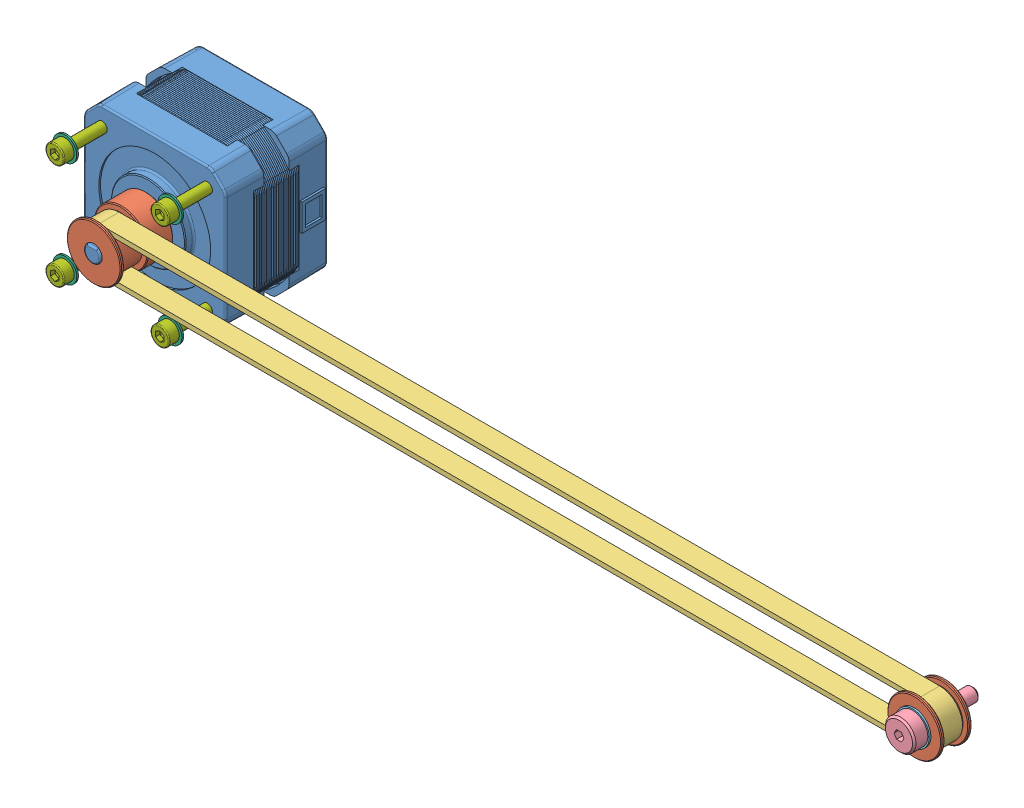
SolidWorks assembly Motion system, configuration Default. Lengths in mm.
Overall size (274.3 42.3 52.5).
15 component instances, 7 part files, 28 mates.
Components (placement in the parent):
- Stepper motor-1: Stepper motor [Default] at (52.9684 86.854 64.8512) x (1 0 0) z (0 -1 0) size (42.8 48.5 42.3)
- 2GT driving pulley-1: 2GT driving pulley [20T long] at (52.9684 86.854 78.3512) x (1 0 0) z (0 -1 0) size (16 15.5 16)
- 2GT driving pulley-2: 2GT driving pulley [20T short] at (294.9684 86.854 84.8512) x (0.57818 -0.815909 0) z (-0.815909 -0.57818 0) size (16 9 16)
- Belt^Motion system-1: Belt^Motion system [Default] at (47.0093 90.3514 89.3512) size (255.49 13.49 6) (virtual)
- Shoulder screw-1: Shoulder screw [Default] at (294.9684 86.854 76.3512) x (1 0 0) z (0 -1 0) size (9 22 9)
- shim-support ring2_din-1: shim-support ring2_din [DIN 988-5x10x0.5] at (294.9684 86.854 84.8512) x (0 0 -1) z (1 0 0) size (0.5 9.81 9.81)
- shim-support ring2_din-2: shim-support ring2_din [DIN 988-5x10x0.5] at (294.9684 86.854 93.8512) x (0 0 1) z (-1 0 0) size (0.5 9.81 9.81)
- plain washer grade a_din-1: plain washer grade a_din [Washer DIN 125 - A 3.2] at (68.4684 71.354 86.3512) x (0 0 -1) z (1 0 0) size (0.5 7 7)
- plain washer grade a_din-2: plain washer grade a_din [Washer DIN 125 - A 3.2] at (37.4684 71.354 86.3512) x (0 0 -1) z (1 0 0) size (0.5 7 7)
- plain washer grade a_din-3: plain washer grade a_din [Washer DIN 125 - A 3.2] at (68.4684 102.354 86.3512) x (0 0 -1) z (1 0 0) size (0.5 7 7)
- plain washer grade a_din-4: plain washer grade a_din [Washer DIN 125 - A 3.2] at (37.4684 102.354 86.3512) x (0 0 -1) z (1 0 0) size (0.5 7 7)
- socket head cap screw_din-1: socket head cap screw_din [DIN 912 M3 x 16 --- 16N] at (68.4684 71.354 89.8512) x (0 0 -1) z (1 0 0) size (19 5.5 5.5)
- socket head cap screw_din-2: socket head cap screw_din [DIN 912 M3 x 16 --- 16N] at (37.4684 71.354 89.8512) x (0 0 -1) z (1 0 0) size (19 5.5 5.5)
- socket head cap screw_din-3: socket head cap screw_din [DIN 912 M3 x 16 --- 16N] at (37.4684 102.354 89.8512) x (0 0 -1) z (1 0 0) size (19 5.5 5.5)
- socket head cap screw_din-4: socket head cap screw_din [DIN 912 M3 x 16 --- 16N] at (68.4684 102.354 89.8512) x (0 0 -1) z (1 0 0) size (19 5.5 5.5)
Mates (geometry in assembly coordinates):
- Concentric21: concentric anti-aligned: cylinder of Shoulder screw-1 through (294.9684 86.854 76.8512) axis (0 0 -1) radius 2.5; cylinder of shim-support ring2_din-1 through (294.9684 86.854 84.8512) axis (0 0 1) radius 2.515
- Coincident20: coincident anti-aligned: plane of Shoulder screw-1 through (299.4684 86.854 94.8512) normal (0 0 -1); plane of shim-support ring2_din-2 through (294.9684 86.854 94.8512) normal (0 0 1)
- Concentric22: concentric anti-aligned: cylinder of shim-support ring2_din-1 through (294.9684 86.854 84.8512) axis (0 0 1) radius 4.905; cylinder of shim-support ring2_din-2 through (294.9684 86.854 94.8512) axis (0 0 -1) radius 4.905
- Coincident12: coincident anti-aligned: plane of plain washer grade a_din-1 through (68.4684 74.854 86.8512) normal (0 0 1); plane of socket head cap screw_din-1 through (68.4684 74.104 86.8512) normal (0 0 -1)
- Coincident13: coincident anti-aligned: plane of plain washer grade a_din-2 through (37.4684 74.854 86.8512) normal (0 0 1); plane of socket head cap screw_din-2 through (37.4684 74.104 86.8512) normal (0 0 -1)
- Coincident15: coincident anti-aligned: plane of plain washer grade a_din-3 through (68.4684 105.854 86.8512) normal (0 0 1); plane of socket head cap screw_din-4 through (68.4684 105.104 86.8512) normal (0 0 -1)
- Coincident14: coincident anti-aligned: plane of plain washer grade a_din-4 through (37.4684 105.854 86.8512) normal (0 0 1); plane of socket head cap screw_din-3 through (37.4684 105.104 86.8512) normal (0 0 -1)
- Distance2: distance = 10.5 mm anti-aligned: plane of Stepper motor-1 through (52.9684 86.854 75.8512) normal (0 0 1); plane of plain washer grade a_din-4 through (37.4684 103.954 86.3512) normal (0 0 -1)
- Coincident22: coincident aligned: plane of plain washer grade a_din-3 through (68.4684 103.954 86.3512) normal (0 0 -1); plane of plain washer grade a_din-4 through (37.4684 103.954 86.3512) normal (0 0 -1)
- Concentric24: concentric aligned: cylinder of plain washer grade a_din-3 through (68.4684 102.354 121.2762) axis (0 0 1) radius 1.6; cylinder of socket head cap screw_din-4 through (68.4684 102.354 121.6012) axis (0 0 1) radius 1.5
- Concentric25: concentric aligned: cylinder of Stepper motor-1 through (68.4684 102.354 70.8512) axis (0 0 1) radius 1.25; cylinder of socket head cap screw_din-4 through (68.4684 102.354 121.6012) axis (0 0 1) radius 1.5
- Concentric26: concentric aligned: cylinder of Stepper motor-1 through (37.4684 102.354 70.8512) axis (0 0 1) radius 1.25; cylinder of socket head cap screw_din-3 through (37.4684 102.354 121.6012) axis (0 0 1) radius 1.5
- Coincident23: coincident aligned: plane of plain washer grade a_din-2 through (37.4684 72.954 86.3512) normal (0 0 -1); plane of plain washer grade a_din-4 through (37.4684 103.954 86.3512) normal (0 0 -1)
- Concentric27: concentric aligned: cylinder of plain washer grade a_din-2 through (37.4684 71.354 121.2762) axis (0 0 1) radius 1.6; cylinder of socket head cap screw_din-2 through (37.4684 71.354 121.6012) axis (0 0 1) radius 1.5
- Concentric28: concentric aligned: cylinder of Stepper motor-1 through (37.4684 71.354 70.8512) axis (0 0 1) radius 1.25; cylinder of socket head cap screw_din-2 through (37.4684 71.354 121.6012) axis (0 0 1) radius 1.5
- Concentric29: concentric aligned: cylinder of Stepper motor-1 through (68.4684 71.354 70.8512) axis (0 0 1) radius 1.25; cylinder of socket head cap screw_din-1 through (68.4684 71.354 121.6012) axis (0 0 1) radius 1.5
- Coincident24: coincident aligned: plane of plain washer grade a_din-1 through (68.4684 72.954 86.3512) normal (0 0 -1); plane of plain washer grade a_din-2 through (37.4684 72.954 86.3512) normal (0 0 -1)
- Concentric30: concentric aligned: cylinder of plain washer grade a_din-1 through (68.4684 71.354 121.2762) axis (0 0 1) radius 1.6; cylinder of socket head cap screw_din-1 through (68.4684 71.354 121.6012) axis (0 0 1) radius 1.5
- Concentric31: concentric aligned: cylinder of plain washer grade a_din-4 through (37.4684 102.354 121.2762) axis (0 0 1) radius 1.6; cylinder of socket head cap screw_din-3 through (37.4684 102.354 121.6012) axis (0 0 1) radius 1.5
- Concentric32: concentric aligned: cylinder of Stepper motor-1 through (52.9684 86.854 75.3512) axis (0 0 -1) radius 2.5; cylinder of 2GT driving pulley-1 through (52.9684 86.854 78.8512) axis (0 0 -1) radius 2.5
- Distance3: distance = 0.5 mm anti-aligned: plane of 2GT driving pulley-1 through (55.4684 86.854 78.3512) normal (0 0 -1); plane of Stepper motor-1 through (56.7184 86.854 77.8512) normal (0 0 1)
- Concentric33: concentric aligned: cylinder of 2GT driving pulley-1 through (52.9684 86.854 78.8512) axis (0 0 -1) radius 6.3662; cylinder of Belt^Motion system-1 through (52.9684 86.854 92.8512) axis (0 0 -1) radius 5.3662
- Width3: width anti-aligned: plane of 2GT driving pulley-1 through (59.3346 86.854 93.3512) normal (0 0 -1); plane of Belt^Motion system-1 through (60.9684 86.854 86.3512) normal (0 0 1); plane of 2GT driving pulley-1 through (52.9684 86.854 92.8512) normal (0 0 1); plane of Belt^Motion system-1 through (52.9684 86.854 86.8512) normal (0 0 -1)
- Width4: width anti-aligned: plane of 2GT driving pulley-2 through (299.5938 80.3267 94.3512) normal (0 0 1); plane of shim-support ring2_din-2 through (296.4138 84.8142 85.3512) normal (0 0 -1); plane of 2GT driving pulley-2 through (294.9684 86.854 94.3512) normal (0 0 -1); plane of shim-support ring2_din-1 through (294.9684 86.854 85.3512) normal (0 0 1)
- Coincident25: coincident anti-aligned: plane of 2GT driving pulley-2 through (299.5938 80.3267 94.3512) normal (0 0 1); plane of shim-support ring2_din-2 through (294.9684 86.854 94.3512) normal (0 0 -1)
- Concentric34: concentric aligned: cylinder of 2GT driving pulley-2 through (294.9684 86.854 85.3512) axis (0 0 -1) radius 6.3662; cylinder of Belt^Motion system-1 through (294.9684 86.854 92.8512) axis (0 0 -1) radius 5.3662
- Concentric35: concentric aligned: cylinder of 2GT driving pulley-2 through (294.9684 86.854 85.3512) axis (0 0 -1) radius 2.5; cylinder of Shoulder screw-1 through (294.9684 86.854 76.8512) axis (0 0 -1) radius 2.5
- Width5: width aligned: plane of 2GT driving pulley-2 through (299.5938 80.3267 86.3512) normal (0 0 1); plane of 2GT driving pulley-2 through (298.6492 81.6598 93.3512) normal (0 0 -1); plane of Belt^Motion system-1 through (52.9684 86.854 92.8512) normal (0 0 1); plane of Belt^Motion system-1 through (52.9684 86.854 86.8512) normal (0 0 -1)
